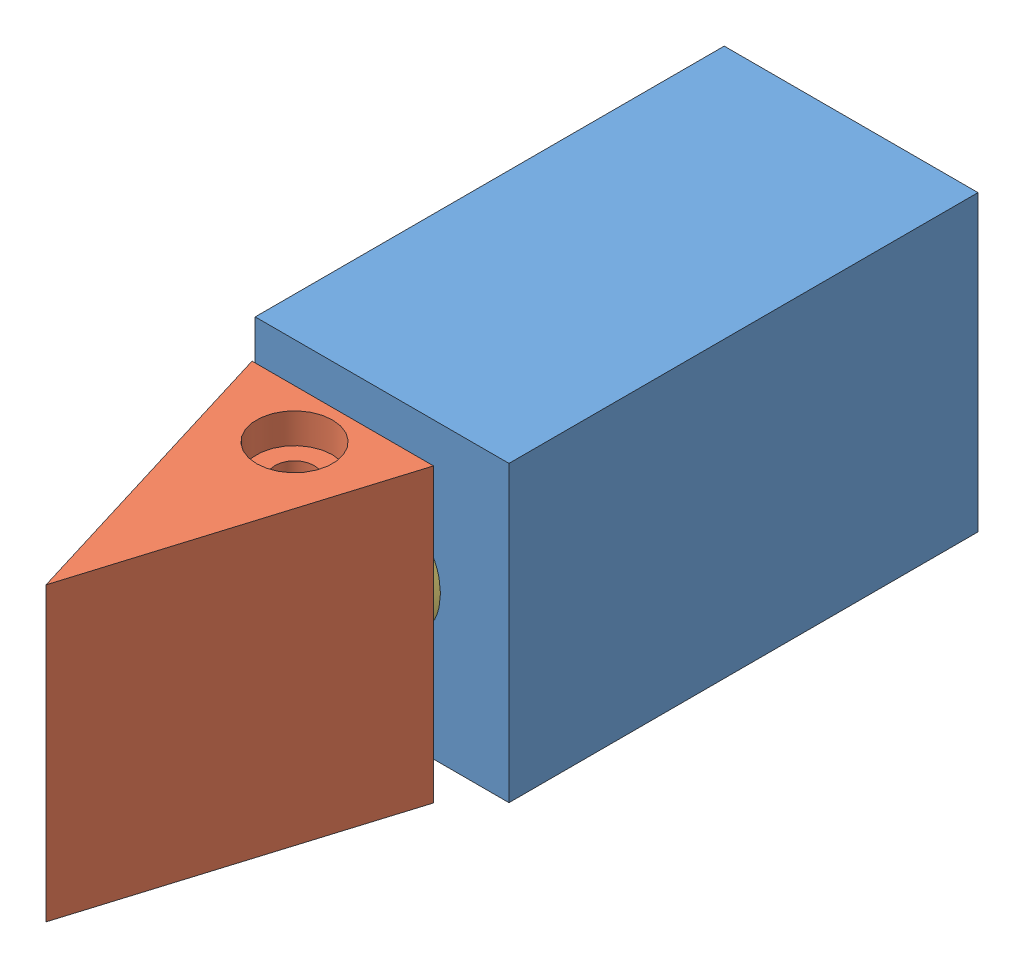
SolidWorks assembly Solenoid Assembly with Insert, configuration Default. Lengths in mm.
Overall size (13.04 15.1 41.35).
3 component instances, 3 part files, 7 mates.
Components (placement in the parent):
- Solenoid_Base-1: Solenoid_Base [Default] at (10.4659 9.6897 0.679) size (13.04 15.1 24.1)
- Solenoid Insert-2: Solenoid Insert [Default] at (16.9859 12.2397 22.2136) size (9.32 15 15.25)
- Solenoid_Plunger-1: Solenoid_Plunger [Default] at (16.9859 17.2397 31.279) x (0 1 0) z (0 0 1) size (6 6 30)
Mates (geometry in assembly coordinates):
- Concentric1: concentric aligned: cylinder of Solenoid_Base-1 through (16.9859 17.2397 0.779) axis (0 0 1) radius 3; cylinder of Solenoid_Plunger-1 through (16.9859 17.2397 1.279) axis (0 0 1) radius 3
- LimitDistance1: limit distance = 2 mm anti-aligned: plane of Solenoid Insert-2 through (21.6282 9.7397 26.779) normal (0 0 -1); plane of Solenoid_Base-1 through (10.4659 9.6897 24.779) normal (0 0 1)
- Concentric2: concentric aligned: cylinder of Solenoid Insert-2 through (16.9859 9.7397 29.279) axis (0 1 0) radius 1; cylinder of Solenoid_Plunger-1 through (16.9859 14.2397 29.279) axis (0 1 0) radius 1
- Concentric3: concentric aligned: cylinder of Solenoid Insert-2 through (21.5309 15.1897 28.279) axis (-1 0 0) radius 1; cylinder of ? through (-20.5206 15.1897 28.279) axis (-1 0 0) radius 1
- Parallel3: parallel anti-aligned: plane of Solenoid_Base-1 through (10.4659 9.6897 24.779) normal (0 0 1); plane of Solenoid Insert-2 through (21.6282 9.7397 26.779) normal (0 0 -1)
- Parallel4: parallel aligned: plane of Solenoid_Base-1 through (10.4659 24.7897 24.779) normal (0 1 0); plane of Solenoid Insert-2 through (16.9859 24.7397 22.2136) normal (0 1 0)
- Distance1: distance = 0.05 mm anti-aligned: plane of Solenoid Insert-2 through (19.8641 18.1897 31.779) normal (0 1 0); plane of Solenoid_Plunger-1 through (13.0975 18.2397 26.279) normal (0 -1 0)
